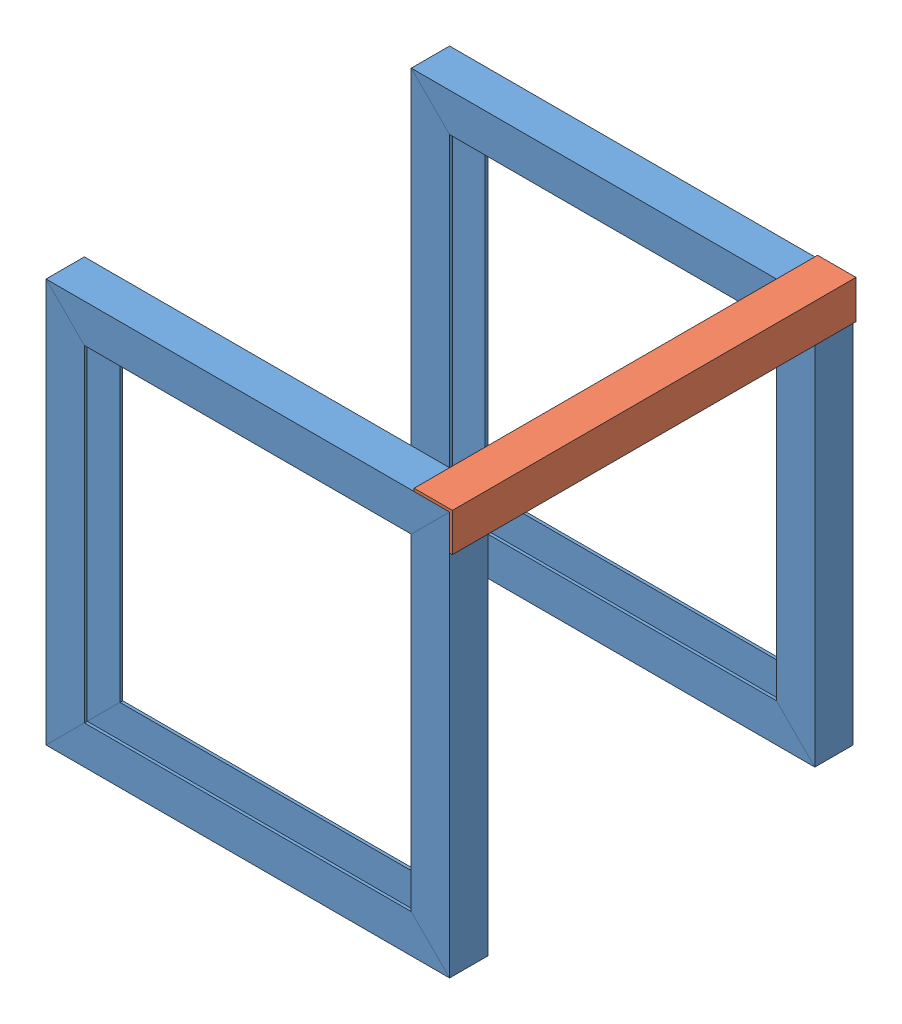
SolidWorks assembly Assem1, configuration Default. Lengths in mm.
Overall size (100.7 100.7 100).
2 component instances, 2 part files, 3 mates.
Components (placement in the parent):
- Frame-1: Frame [Default<As Machined>] at origin size (100 100 100)
- cut-1: cut [Default] at (45.95 45.95 -50) x (0 1 0) z (0 0 1) size (9.5 9.5 100)
Mates (geometry in assembly coordinates):
- Coincident1: coincident: plane of assembly; plane of assembly; plane of Frame-1 through (50 -50 -100) normal (1 0 0); plane of cut-1 through (50 50 0) normal (-1 0 0)
- Coincident2: coincident: plane of assembly; plane of assembly; plane of Frame-1 through (50 50 -100) normal (0 1 0); plane of cut-1 through (41.9 50 0) normal (0 -1 0)
- Width1: width: plane of assembly; plane of assembly; plane of assembly; plane of assembly; plane of Frame-1 through (50 50 0) normal (0 0 1); plane of Frame-1 through (50 -50 -100) normal (0 0 -1); plane of cut-1 through (45.95 45.95 0) normal (0 0 1); plane of cut-1 through (45.95 45.95 -100) normal (0 0 -1)
